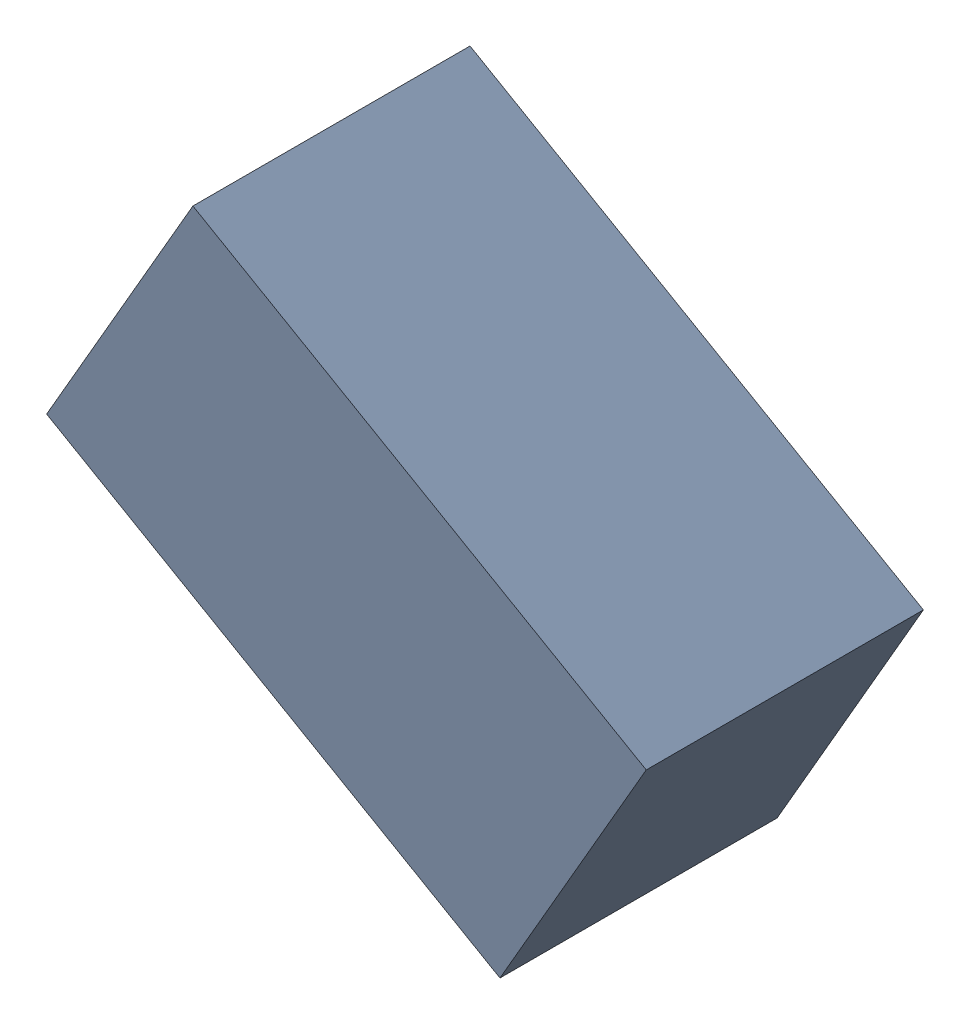
SolidWorks assembly R1_TDA3, configuration Standard. Lengths in mm.
Overall size (1.95 1.67 0.9).
2 component instances, 1 part files, 0 mates.
Components (placement in the parent):
- 885544144-1: 885544144 [Standard] at (45.0024 -21.7449 0) size (1.95 1.67 0.9)
  - Extruded_14-1: Extruded_14 [Standard] at origin size (1.95 1.67 0.9)
